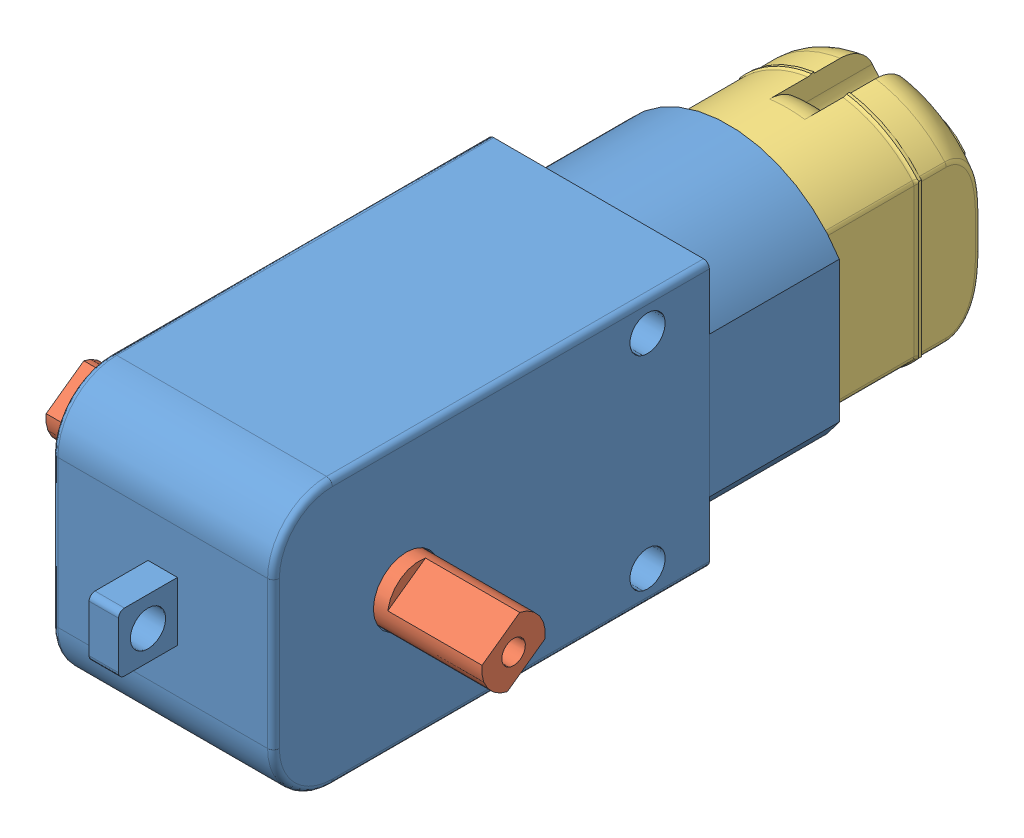
SolidWorks assembly DC Motor Gearbox, configuration Default. Lengths in mm.
Overall size (37 22.5 70).
3 component instances, 3 part files, 11 mates.
Components (placement in the parent):
- Gearbox-1: Gearbox [Default] at (19.5167 31.236 22.8921) size (18.83 22.5 53)
- output shaft-1: output shaft [Default] at (19.5167 31.236 48.6121) x (1 0 0) z (0 0.813523 0.581533) size (37 5.4 5.4)
- motor-1: motor [Default] at (19.5167 31.236 -2.1079) size (17.2 19.92 37.8)
Mates (geometry in assembly coordinates):
- Concentric1: concentric anti-aligned: cylinder of Gearbox-1 through (10.1167 31.236 48.6121) axis (1 0 0) radius 2.8; cylinder of output shaft-1 through (38.0167 31.236 48.6121) axis (-1 0 0) radius 2.7
- Coincident2: coincident aligned: plane of Gearbox-1 through (19.5167 31.236 22.8921) normal (1 0 0); plane of output shaft-1 through (19.5167 31.236 48.6121) normal (1 0 0)
- Concentric2: concentric aligned: cylinder of Gearbox-1 through (19.5167 31.236 22.8921) axis (0 0 -1) radius 9.9657; cylinder of motor-1 through (19.5167 31.236 22.8921) axis (0 0 -1) radius 9.9
- Parallel1: parallel anti-aligned: plane of Gearbox-1 through (27.7455 36.8576 22.8921) normal (-1 0 0); plane of motor-1 through (27.0167 37.6982 22.8921) normal (1 0 0)
- Coincident3: coincident anti-aligned: plane of Gearbox-1 through (19.5167 31.236 22.8921) normal (0 0 -1); plane of motor-1 through (19.5167 31.236 22.8921) normal (0 0 1)
- Concentric3: concentric anti-aligned: cylinder of output shaft-1 through (38.0167 31.236 48.6121) axis (-1 0 0) radius 2.7; cylinder of ? through (-0.6833 31.236 48.3921) axis (1 0 0) radius 3.25
- Coincident4: coincident anti-aligned: plane of output shaft-1 through (1.0167 31.236 48.6121) normal (-1 0 0); plane of ? through (1.0167 31.236 48.3921) normal (1 0 0)
- Parallel2: parallel aligned: plane of output shaft-1 through (9.0167 30.8746 45.9364) normal (0 -0.813523 -0.581533); plane of ? through (-0.6833 34.4651 48.7607) normal (0 -0.623012 -0.782212)
- Parallel3: parallel anti-aligned: plane of output shaft-1 through (30.0167 33.8847 48.0881) normal (0 0.813523 0.581533); plane of ? through (30.0167 28.7912 46.2508) normal (0 0.997873 -0.065186)
- Concentric4: concentric anti-aligned: cylinder of output shaft-1 through (38.0167 31.236 48.6121) axis (-1 0 0) radius 2.7; cylinder of ? through (30.0167 31.236 48.3921) axis (1 0 0) radius 3.25
- Coincident7: coincident anti-aligned: plane of output shaft-1 through (38.0167 31.236 48.6121) normal (1 0 0); plane of ? through (38.0167 31.236 48.3921) normal (-1 0 0)
